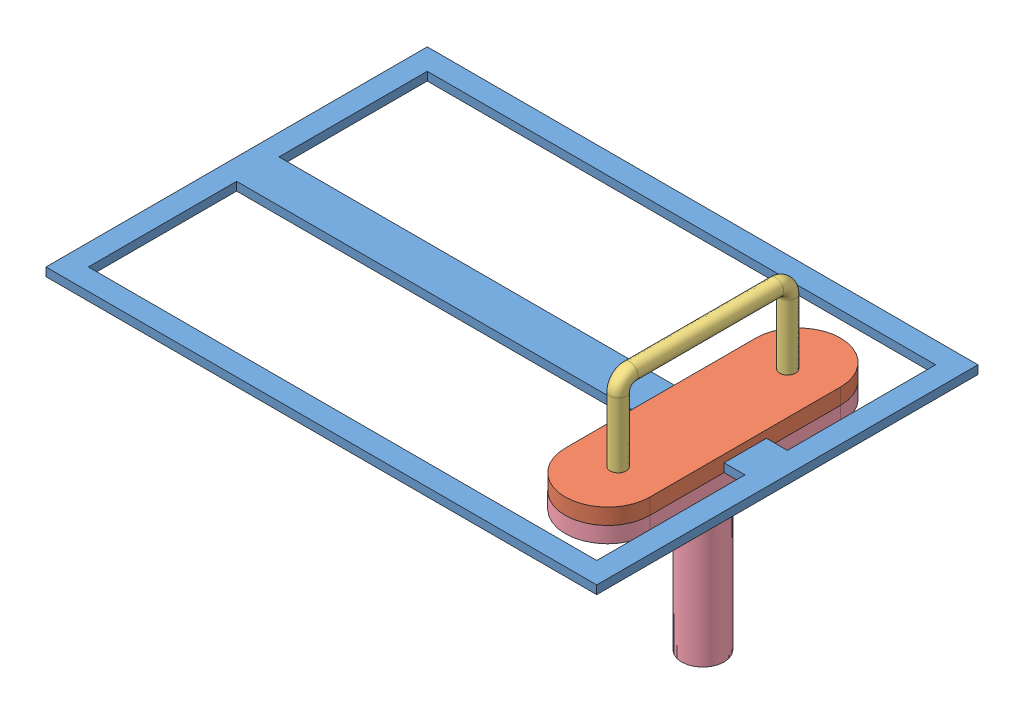
SolidWorks assembly Killswitch4, configuration Default. Lengths in mm.
Overall size (165.1 85.72 114.3).
4 component instances, 4 part files, 8 mates.
Components (placement in the parent):
- Panel-1: Panel [Default] at origin size (165.1 2.54 114.3)
- RotatingPiece-1: RotatingPiece [Default] at (57.2267 4.7625 0) x (-1 0 0) z (0 0 1) size (25.4 4.76 82.55)
- 1568A630-1: 1568A630 [1568A63] at (57.2267 27.7812 0) x (0 0 -1) z (-1 0 0) size (55.56 25.63 4.76)
- RotatingPieceBottom-1: RotatingPieceBottom [Default] at (57.2267 0 0) x (-1 0 0) z (0 0 1) size (25.4 55.56 82.55)
Mates (geometry in assembly coordinates):
- Coincident1: coincident anti-aligned: plane of Panel-1 through (-156.3308 2.54 0) normal (0 1 0); plane of RotatingPiece-1 through (69.9267 2.54 6.35) normal (0 -1 0)
- Coincident2: coincident anti-aligned: plane of Panel-1 through (-156.3308 2.54 6.35) normal (0 0 1); plane of RotatingPiece-1 through (44.5267 2.54 6.35) normal (0 0 -1)
- Concentric1: concentric aligned: circle of RotatingPiece-1; circle of 1568A630-1
- Coincident3: coincident anti-aligned: plane of RotatingPiece-1 through (57.2267 4.7625 -28.575) normal (0 1 0); plane of 1568A630-1 through (57.2267 4.7625 25.4) normal (0 -1 0)
- Concentric2: concentric anti-aligned: circle of RotatingPiece-1; circle of 1568A630-1
- Coincident4: coincident anti-aligned: plane of RotatingPiece-1 through (57.2267 0 -28.575) normal (0 -1 0); plane of RotatingPieceBottom-1 through (57.2267 0 -28.575) normal (0 1 0)
- Coincident5: coincident aligned: plane of RotatingPiece-1 through (44.5267 0 -28.575) normal (-1 0 0); plane of RotatingPieceBottom-1 through (44.5267 -4.7625 -28.575) normal (-1 0 0)
- Concentric3: concentric aligned: cylinder of RotatingPiece-1 through (57.2267 0 28.575) axis (0 1 0) radius 12.7; cylinder of RotatingPieceBottom-1 through (57.2267 -4.7625 28.575) axis (0 1 0) radius 12.7
